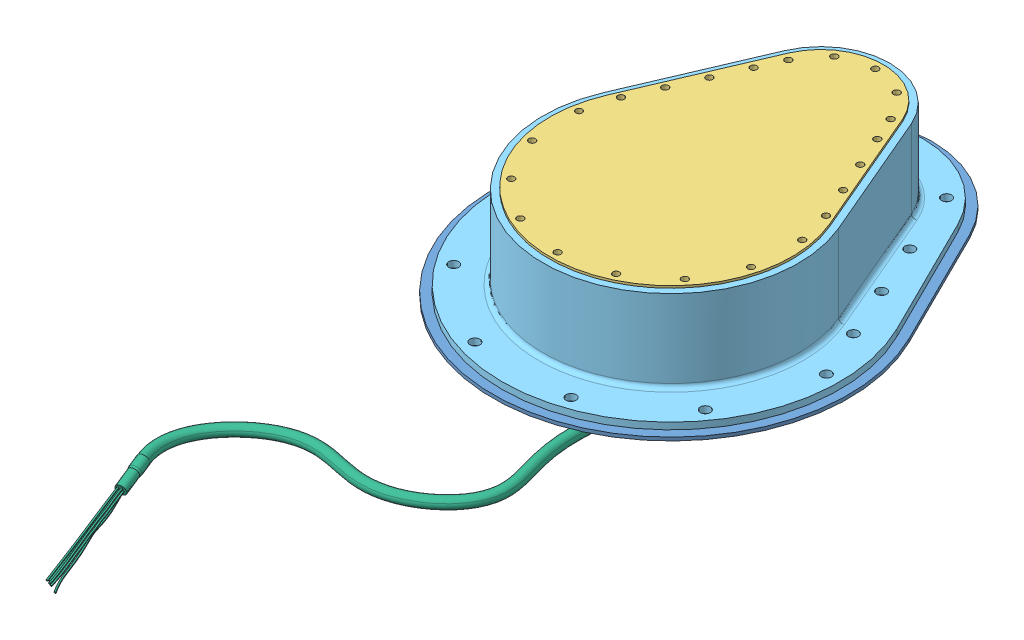
SolidWorks assembly gearbox ass, configuration Default. Lengths in mm.
Overall size (181.08 91.26 325.33).
6 component instances, 6 part files, 14 mates.
Components (placement in the parent):
- motor plate-1: motor plate [Default] at (67.4812 84.8892 185.4808) size (160 1.5 197.5)
- encoder_gear-1: encoder_gear [Default] at (70.3732 100.1328 178.2244) x (0 1 0) z (0.997979 0 -0.063544) size (6 92.93 92.93)
- motor cover 2-1: motor cover 2 [Default] at (67.4812 127.3892 164.9808) x (-1 0 0) z (0 -1 0) size (109 150 3)
- motor_gear-1: motor_gear [Default] at (65.6341 93.261 115.6899) x (0 1 0) z (-0.095668 0 -0.995413) size (6 47.84 48)
- motor cover-1: motor cover [Default] at (67.4812 86.3892 185.4808) size (152 40 189.5)
- Encoder Rotary -1: Encoder Rotary  [Default] at (67.4812 46.4892 185.4808) x (0.997979 0 -0.063544) z (0 1 0) size (119.56 221.18 61.66)
Mates (geometry in assembly coordinates):
- Concentric1: concentric anti-aligned: cylinder of motor_gear-1 through (67.4812 144.3893 117.9808) axis (0 -1 0) radius 4; circle of motor plate-1
- Distance1: distance = 8 mm anti-aligned: plane of motor_gear-1 through (67.4812 94.3892 117.9808) normal (0 -1 0); plane of motor plate-1 through (67.4812 86.3892 117.9808) normal (0 1 0)
- Concentric2: concentric anti-aligned: cylinder of encoder_gear-1 through (67.4812 144.3893 185.4808) axis (0 -1 0) radius 3; circle of motor plate-1
- Coincident2: coincident aligned: plane of encoder_gear-1 through (67.4812 100.3892 185.4808) normal (0 1 0); plane of motor_gear-1 through (67.4812 100.3892 117.9808) normal (0 1 0)
- GearMate1: gear = 2 : 1 mm: circle of motor_gear-1; cylinder of encoder_gear-1 through (67.4812 84.3892 185.4808) axis (0 -1 0) radius 46.5
- Concentric3: concentric anti-aligned: circle of motor plate-1; cylinder of motor cover-1 through (67.4812 89.3892 77.9808) axis (0 -1 0) radius 2.25
- Concentric4: concentric aligned: cylinder of motor plate-1 through (89.1124 86.3892 252.0547) axis (0 -1 0) radius 2.25; cylinder of motor cover-1 through (89.1124 89.3892 252.0547) axis (0 -1 0) radius 2.25
- Coincident5: coincident anti-aligned: plane of motor plate-1 through (67.4812 86.3892 117.9808) normal (0 1 0); plane of motor cover-1 through (67.4812 86.3892 185.4808) normal (0 -1 0)
- Coincident6: coincident anti-aligned: plane of motor cover 2-1 through (67.4812 124.3892 164.9808) normal (0 -1 0); plane of motor cover-1 through (67.4812 124.3892 117.9808) normal (0 1 0)
- Concentric5: concentric aligned: cylinder of motor cover 2-1 through (67.4812 124.3892 93.4808) axis (0 1 0) radius 1.5; circle of motor cover-1
- Concentric6: concentric aligned: cylinder of motor cover 2-1 through (67.4812 124.3892 236.4808) axis (0 1 0) radius 1.5; cylinder of motor cover-1 through (67.4812 86.3892 236.4808) axis (0 1 0) radius 1.5
- Concentric7: concentric anti-aligned: cylinder of Encoder Rotary -1 through (67.4812 80.8892 185.4808) axis (0 1 0) radius 10; cylinder of motor plate-1 through (67.4812 86.3892 185.4808) axis (0 -1 0) radius 10
- Coincident8: coincident anti-aligned: plane of encoder_gear-1 through (70.9742 90.7396 187.6632) normal (-0.063544 0 -0.997979); plane of Encoder Rotary -1 through (65.8374 97.7892 187.9903) normal (0.063544 0 0.997979)
- Distance2: distance = 4 mm anti-aligned: plane of motor plate-1 through (67.4812 84.8892 117.9808) normal (0 -1 0); plane of Encoder Rotary -1 through (67.4812 80.8892 185.4808) normal (0 1 0)
